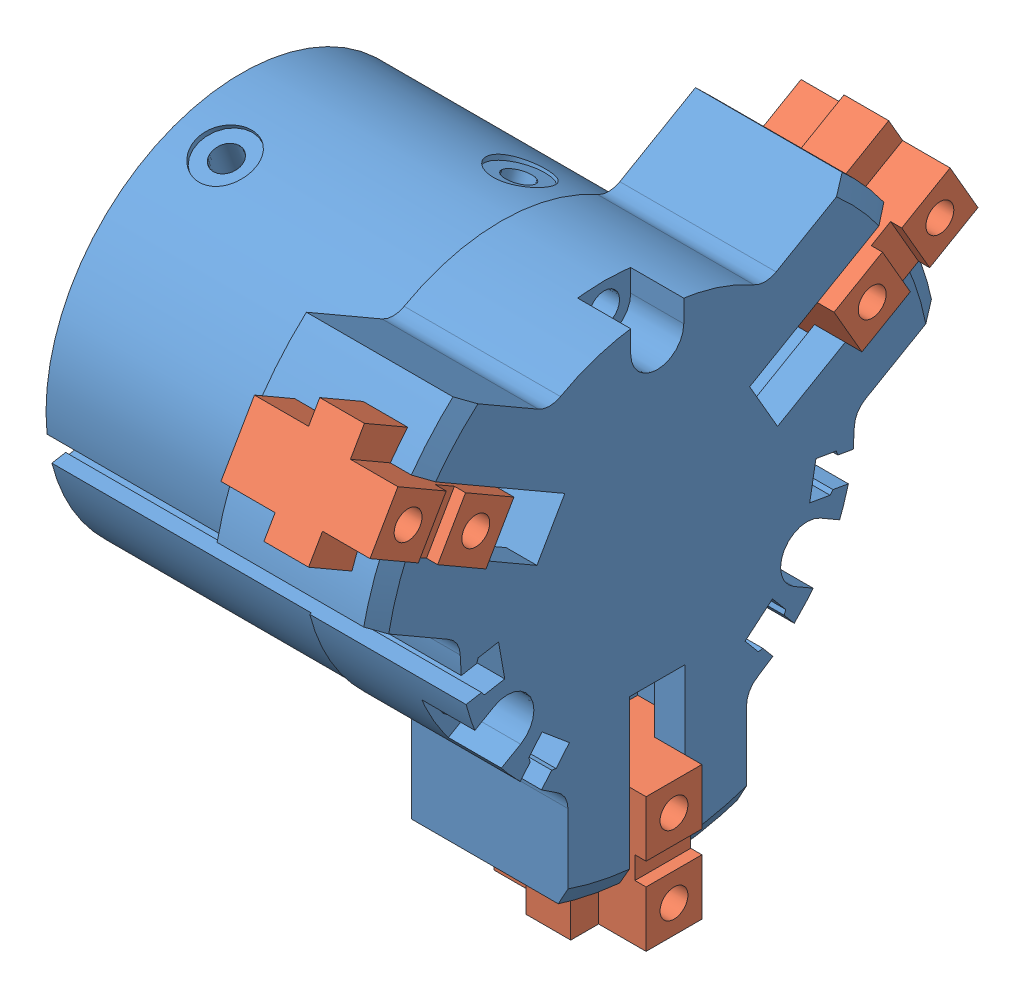
SolidWorks assembly MHSL3-50D, configuration MHSL3-50D. Lengths in mm.
Overall size (77.5 98.66 113.92).
4 component instances, 2 part files, 7 mates.
Components (placement in the parent):
- MHSL3-50D_MHSL-Body-1: MHSL3-50D_MHSL-Body [50] x (-1 0 0) z (0 0 -1) size (74.5 90.6 101.7)
- MHSL3-50D_MHSL-Finger-1: MHSL3-50D_MHSL-Finger [50] at (61 -48 0) x (-1 0 0) z (0 0 1) size (26.2 24 20)
- MHSL3-50D_MHSL-Finger-2: MHSL3-50D_MHSL-Finger [50] at (61 24 41.5692) x (-1 0 0) z (0 0.866025 -0.5) size (26.2 24 20)
- MHSL3-50D_MHSL-Finger-3: MHSL3-50D_MHSL-Finger [50] at (61 24 -41.5692) x (-1 0 0) z (0 -0.866025 -0.5) size (26.2 24 20)
Mates (geometry in assembly coordinates):
- Coincident1: coincident anti-aligned: plane of MHSL3-50D_MHSL-Body-1 through (0 0 0) normal (-1 0 0); plane of assembly through (0 0 0) normal (1 0 0)
- Coincident2: coincident aligned: plane of MHSL3-50D_MHSL-Body-1 through (0 0 0) normal (0 1 0); plane of assembly through (0 0 0) normal (0 1 0)
- Coincident3: coincident anti-aligned: plane of MHSL3-50D_MHSL-Body-1 through (0 0 0) normal (0 0 -1); plane of assembly through (0 0 0) normal (0 0 1)
- Coincident4: coincident anti-aligned: plane of MHSL3-50D_MHSL-Body-1 through (61 -22 5) normal (1 0 0); plane of MHSL3-50D_MHSL-Finger-1 through (61 -60 5) normal (-1 0 0)
- Coincident6: coincident anti-aligned: plane of MHSL3-50D_MHSL-Body-1 through (0 0 0) normal (0 0 -1); plane of MHSL3-50D_MHSL-Finger-1 through (61 -48 0) normal (0 0 1)
- DO(GripperOpen): distance = 60 mm anti-aligned: plane of MHSL3-50D_MHSL-Body-1 through (0 0 0) normal (0 1 0); plane of MHSL3-50D_MHSL-Finger-1 through (77.5 -60 5) normal (0 -1 0)
- DC(GripperClose): distance = 46 mm anti-aligned: plane of MHSL3-50D_MHSL-Body-1 through (0 0 0) normal (0 1 0); plane of MHSL3-50D_MHSL-Finger-1 through (58 -42 4) normal (0 -1 0)
